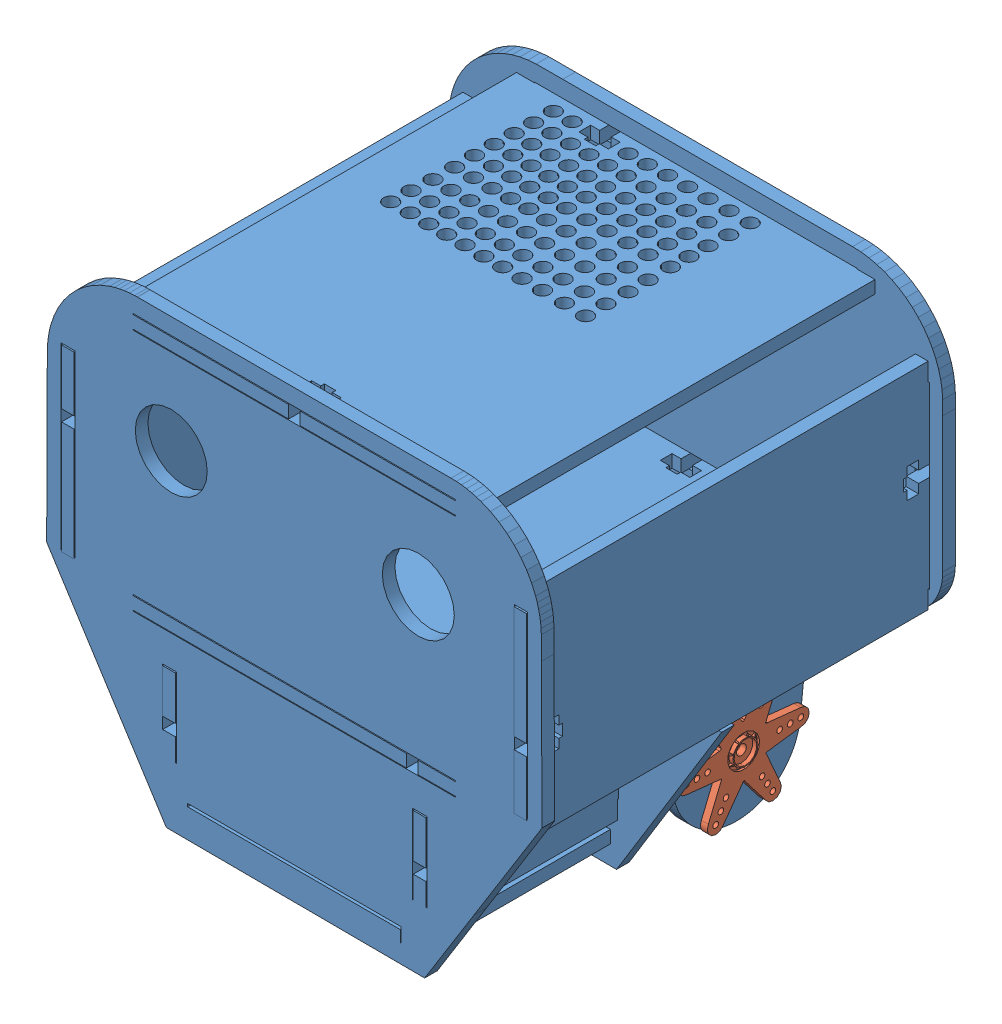
SolidWorks assembly head, configuration Default. Lengths in mm.
Overall size (137.53 133.68 115.01).
2 component instances, 2 part files, 2 mates.
Components (placement in the parent):
- head_100-1: head_100 [Default] at origin size (137.53 127.54 115.01)
- servo_arm_6_sided-2: servo_arm_6_sided [Default] at (107.2186 30.578 30.1948) x (0 0.859207 0.511627) z (0 0.511627 -0.859207) size (36.45 6.25 32.2)
Mates (geometry in assembly coordinates):
- Coincident1: coordinate: point of head_100-1
- ProfileCenter1: profile center anti-aligned: circle of head_100-1; circle of servo_arm_6_sided-2
